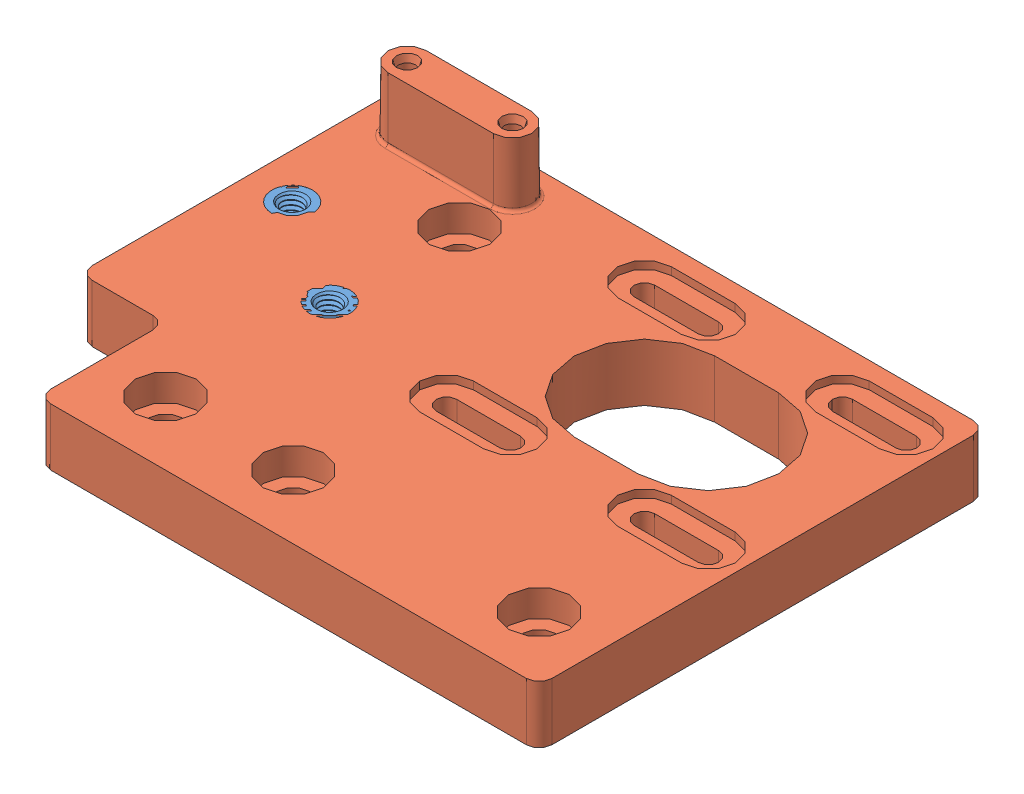
SolidWorks assembly left_motor_plate_with_inserts, configuration Default. Lengths in mm.
Overall size (92 19.4 70).
3 component instances, 2 part files, 4 mates.
Components (placement in the parent):
- m4_heat_set_insert_long_94180A353-1: m4_heat_set_insert_long_94180A353 [94180A353] at (-81.429 393.0105 -31.0093) size (6.35 8.38 6.35)
- motor_corner_bracket-1: motor_corner_bracket [Left Motor Corner Bracket] at (-74.929 384.0105 15.3157) size (92 19.4 70)
- m4_heat_set_insert_long_94180A353-2: m4_heat_set_insert_long_94180A353 [94180A353] at (-64.929 393.0105 -20.3843) size (6.35 8.38 6.35)
Mates (geometry in assembly coordinates):
- Coincident1594070879: coincident aligned: plane of motor_corner_bracket-1 through (-74.929 393.0105 15.3157) normal (0 1 0); plane of m4_heat_set_insert_long_94180A353-1 through (-81.429 393.0105 -31.0093) normal (0 1 0)
- Concentric754010286: concentric anti-aligned: cylinder of motor_corner_bracket-1 through (-81.429 393.0105 -31.0093) axis (0 -1 0) radius 2.7; unknown of m4_heat_set_insert_long_94180A353-1
- Coincident1594070880: coincident aligned: plane of motor_corner_bracket-1 through (-74.929 393.0105 15.3157) normal (0 1 0); plane of m4_heat_set_insert_long_94180A353-2 through (-64.929 393.0105 -20.3843) normal (0 1 0)
- Concentric754010287: concentric anti-aligned: cylinder of motor_corner_bracket-1 through (-64.929 393.0105 -20.3843) axis (0 -1 0) radius 2.7; unknown of m4_heat_set_insert_long_94180A353-2
